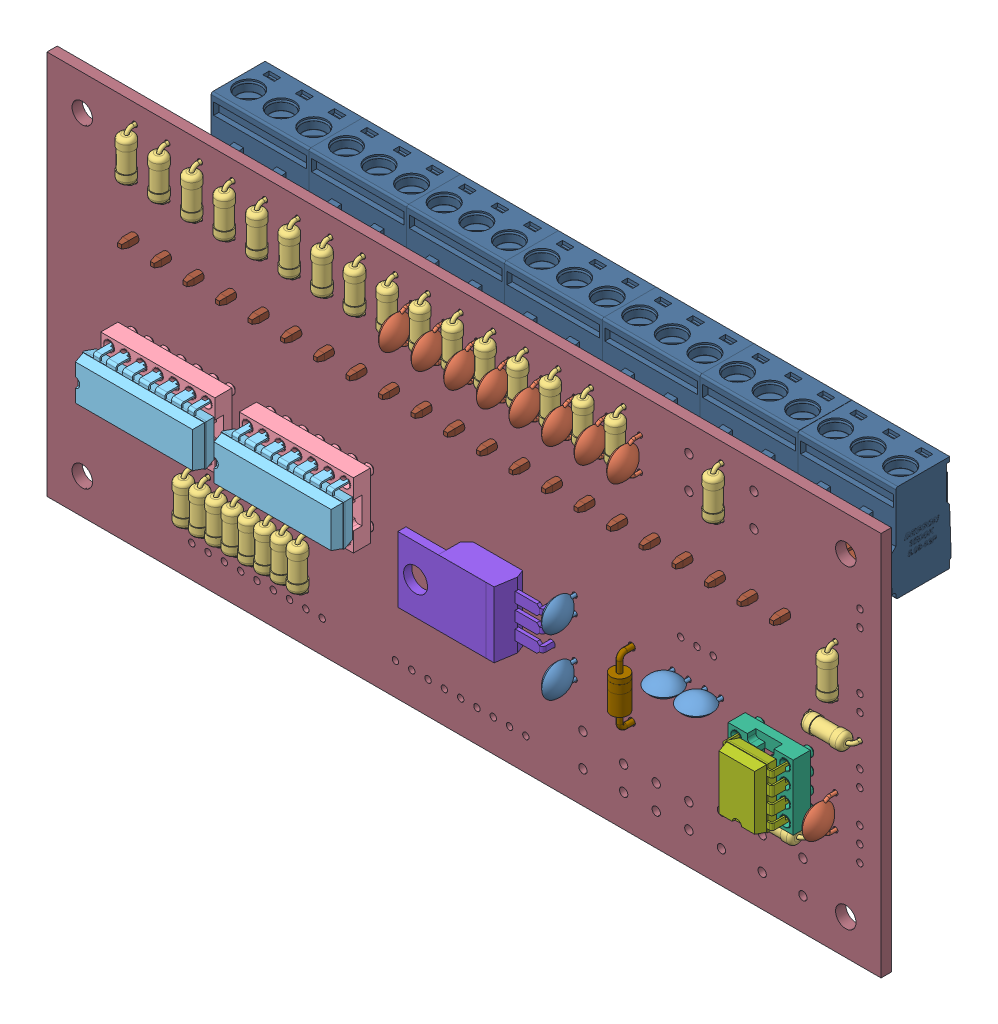
SolidWorks assembly minilab-export, configuration Predeterminado. Lengths in mm.
Overall size (130 60 30.78).
130 component instances, 13 part files, 0 mates.
Components (placement in the parent):
- minilab.step-1: minilab.step [Predeterminado] at (3.7851 -4.1028 7.8934) size (130 60 30.78)
  - C_Disc_D5.0mm_W2.5mm_P2.50mm.step-1: C_Disc_D5.0mm_W2.5mm_P2.50mm.step [Predeterminado] at (175.26 -113.03 1.65) x (0 -1 0) z (0 0 1) size (5 2.5 7.1)
    - SOLID.step-1: SOLID.step [Predeterminado] at origin size (5 2.5 7.1)
  - C_Disc_D5.0mm_W2.5mm_P5.00mm.step-1: C_Disc_D5.0mm_W2.5mm_P5.00mm.step [Predeterminado] at (170.18 -82.55 1.65) x (0 1 0) z (0 0 1) size (5.5 2.5 7.1)
    - SOLID-0.step-1: SOLID-0.step [Predeterminado] at origin size (5.5 2.5 7.1)
  - R_Axial_DIN0207_L6.3mm_D2.5mm_P7.62mm_Horizontal.step-1: R_Axial_DIN0207_L6.3mm_D2.5mm_P7.62mm_Horizontal.step [Predeterminado] at (121.92 -82.55 1.65) x (0 1 0) z (0 0 1) size (8.22 2.5 5.5)
    - SOLID-1.step-1: SOLID-1.step [Predeterminado] at origin size (8.22 2.5 5.5)
  - C_Disc_D5.0mm_W2.5mm_P2.50mm.step_2-1: C_Disc_D5.0mm_W2.5mm_P2.50mm.step_2 [Predeterminado] at (190.52 -106.68 1.65) size (5 2.5 7.1)
    - SOLID.step-1: SOLID.step [Predeterminado] at origin size (5 2.5 7.1)
  - R_Axial_DIN0207_L6.3mm_D2.5mm_P7.62mm_Horizontal.step_2-1: R_Axial_DIN0207_L6.3mm_D2.5mm_P7.62mm_Horizontal.step_2 [Predeterminado] at (182.88 -74.93 1.65) x (0 -1 0) z (0 0 1) size (8.22 2.5 5.5)
    - SOLID-1.step-1: SOLID-1.step [Predeterminado] at origin size (8.22 2.5 5.5)
  - R_Axial_DIN0207_L6.3mm_D2.5mm_P7.62mm_Horizontal.step_3-1: R_Axial_DIN0207_L6.3mm_D2.5mm_P7.62mm_Horizontal.step_3 [Predeterminado] at (198.12 -82.55 1.65) x (0 1 0) z (0 0 1) size (8.22 2.5 5.5)
    - SOLID-1.step-1: SOLID-1.step [Predeterminado] at origin size (8.22 2.5 5.5)
  - C_Disc_D5.0mm_W2.5mm_P5.00mm.step_2-1: C_Disc_D5.0mm_W2.5mm_P5.00mm.step_2 [Predeterminado] at (175.26 -82.51 1.65) x (0 1 0) z (0 0 1) size (5.5 2.5 7.1)
    - SOLID-0.step-1: SOLID-0.step [Predeterminado] at origin size (5.5 2.5 7.1)
  - DIP-14_W7.62mm_Socket.step-1: DIP-14_W7.62mm_Socket.step [Predeterminado] at (106.675 -110.48 1.65) x (0 1 0) z (0 0 1) size (10.16 17.78 7.79)
    - SOLID-2.step-1: SOLID-2.step [Predeterminado] at origin size (10.16 17.78 7.79)
  - DIP-14_W7.62mm.step-1: DIP-14_W7.62mm.step [Predeterminado] at (106.675 -110.48 5.65) x (0 1 0) z (0 0 1) size (7.87 19.05 6.98)
    - SOLID-3.step-1: SOLID-3.step [Predeterminado] at origin size (7.87 19.05 6.98)
  - DIP-8_W7.62mm_Socket.step-1: DIP-8_W7.62mm_Socket.step [Predeterminado] at (212.06 -114.3 1.65) x (-1 0 0) z (0 0 1) size (10.16 10.16 7.79)
    - SOLID-4.step-1: SOLID-4.step [Predeterminado] at origin size (10.16 10.16 7.79)
  - DIP-8_W7.62mm.step-1: DIP-8_W7.62mm.step [Predeterminado] at (212.06 -114.3 5.65) x (-1 0 0) z (0 0 1) size (7.87 9.27 6.98)
    - SOLID-5.step-1: SOLID-5.step [Predeterminado] at origin size (7.87 9.27 6.98)
  - R_Axial_DIN0207_L6.3mm_D2.5mm_P7.62mm_Horizontal.step_4-1: R_Axial_DIN0207_L6.3mm_D2.5mm_P7.62mm_Horizontal.step_4 [Predeterminado] at (127 -82.55 1.65) x (0 1 0) z (0 0 1) size (8.22 2.5 5.5)
    - SOLID-1.step-1: SOLID-1.step [Predeterminado] at origin size (8.22 2.5 5.5)
  - R_Axial_DIN0207_L6.3mm_D2.5mm_P7.62mm_Horizontal.step_5-1: R_Axial_DIN0207_L6.3mm_D2.5mm_P7.62mm_Horizontal.step_5 [Predeterminado] at (125.73 -116.84 1.65) x (0 -1 0) z (0 0 1) size (8.22 2.5 5.5)
    - SOLID-1.step-1: SOLID-1.step [Predeterminado] at origin size (8.22 2.5 5.5)
  - C_Disc_D5.0mm_W2.5mm_P5.00mm.step_3-1: C_Disc_D5.0mm_W2.5mm_P5.00mm.step_3 [Predeterminado] at (149.86 -82.55 1.65) x (0 1 0) z (0 0 1) size (5.5 2.5 7.1)
    - SOLID-0.step-1: SOLID-0.step [Predeterminado] at origin size (5.5 2.5 7.1)
  - TO-220-3_Horizontal_TabUp.step-1: TO-220-3_Horizontal_TabUp.step [Predeterminado] at (171.66 -107.46 1.65) x (0 -1 0) z (0 0 1) size (10.25 19.74 12.58)
    - SOLID-6.step-1: SOLID-6.step [Predeterminado] at origin size (10.25 19.74 12.58)
  - R_Axial_DIN0207_L6.3mm_D2.5mm_P7.62mm_Horizontal.step_6-1: R_Axial_DIN0207_L6.3mm_D2.5mm_P7.62mm_Horizontal.step_6 [Predeterminado] at (133.35 -116.84 1.65) x (0 -1 0) z (0 0 1) size (8.22 2.5 5.5)
    - SOLID-1.step-1: SOLID-1.step [Predeterminado] at origin size (8.22 2.5 5.5)
  - R_Axial_DIN0207_L6.3mm_D2.5mm_P7.62mm_Horizontal.step_7-1: R_Axial_DIN0207_L6.3mm_D2.5mm_P7.62mm_Horizontal.step_7 [Predeterminado] at (120.65 -116.84 1.65) x (0 -1 0) z (0 0 1) size (8.22 2.5 5.5)
    - SOLID-1.step-1: SOLID-1.step [Predeterminado] at origin size (8.22 2.5 5.5)
  - C_Disc_D5.0mm_W2.5mm_P5.00mm.step_4-1: C_Disc_D5.0mm_W2.5mm_P5.00mm.step_4 [Predeterminado] at (180.34 -82.51 1.65) x (0 1 0) z (0 0 1) size (5.5 2.5 7.1)
    - SOLID-0.step-1: SOLID-0.step [Predeterminado] at origin size (5.5 2.5 7.1)
  - R_Axial_DIN0207_L6.3mm_D2.5mm_P7.62mm_Horizontal.step_8-1: R_Axial_DIN0207_L6.3mm_D2.5mm_P7.62mm_Horizontal.step_8 [Predeterminado] at (115.57 -116.84 1.65) x (0 -1 0) z (0 0 1) size (8.22 2.5 5.5)
    - SOLID-1.step-1: SOLID-1.step [Predeterminado] at origin size (8.22 2.5 5.5)
  - R_Axial_DIN0207_L6.3mm_D2.5mm_P7.62mm_Horizontal.step_9-1: R_Axial_DIN0207_L6.3mm_D2.5mm_P7.62mm_Horizontal.step_9 [Predeterminado] at (157.48 -74.93 1.65) x (0 -1 0) z (0 0 1) size (8.22 2.5 5.5)
    - SOLID-1.step-1: SOLID-1.step [Predeterminado] at origin size (8.22 2.5 5.5)
  - R_Axial_DIN0207_L6.3mm_D2.5mm_P7.62mm_Horizontal.step_10-1: R_Axial_DIN0207_L6.3mm_D2.5mm_P7.62mm_Horizontal.step_10 [Predeterminado] at (142.24 -82.55 1.65) x (0 1 0) z (0 0 1) size (8.22 2.5 5.5)
    - SOLID-1.step-1: SOLID-1.step [Predeterminado] at origin size (8.22 2.5 5.5)
  - C_Disc_D5.0mm_W2.5mm_P5.00mm.step_5-1: C_Disc_D5.0mm_W2.5mm_P5.00mm.step_5 [Predeterminado] at (215.88 -110.54 1.65) x (0 -1 0) z (0 0 1) size (5.5 2.5 7.1)
    - SOLID-0.step-1: SOLID-0.step [Predeterminado] at origin size (5.5 2.5 7.1)
  - R_Axial_DIN0207_L6.3mm_D2.5mm_P7.62mm_Horizontal.step_11-1: R_Axial_DIN0207_L6.3mm_D2.5mm_P7.62mm_Horizontal.step_11 [Predeterminado] at (123.19 -116.84 1.65) x (0 -1 0) z (0 0 1) size (8.22 2.5 5.5)
    - SOLID-1.step-1: SOLID-1.step [Predeterminado] at origin size (8.22 2.5 5.5)
  - D_DO-41_SOD81_P10.16mm_Horizontal.step-1: D_DO-41_SOD81_P10.16mm_Horizontal.step [Predeterminado] at (184.15 -106.68 1.65) x (0 -1 0) z (0 0 1) size (10.96 2.72 5.71)
    - SOLID-7.step-1: SOLID-7.step [Predeterminado] at origin size (10.96 2.72 5.71)
  - R_Axial_DIN0207_L6.3mm_D2.5mm_P7.62mm_Horizontal.step_12-1: R_Axial_DIN0207_L6.3mm_D2.5mm_P7.62mm_Horizontal.step_12 [Predeterminado] at (116.84 -82.55 1.65) x (0 1 0) z (0 0 1) size (8.22 2.5 5.5)
    - SOLID-1.step-1: SOLID-1.step [Predeterminado] at origin size (8.22 2.5 5.5)
  - R_Axial_DIN0207_L6.3mm_D2.5mm_P7.62mm_Horizontal.step_13-1: R_Axial_DIN0207_L6.3mm_D2.5mm_P7.62mm_Horizontal.step_13 [Predeterminado] at (132.08 -82.55 1.65) x (0 1 0) z (0 0 1) size (8.22 2.5 5.5)
    - SOLID-1.step-1: SOLID-1.step [Predeterminado] at origin size (8.22 2.5 5.5)
  - R_Axial_DIN0207_L6.3mm_D2.5mm_P7.62mm_Horizontal.step_14-1: R_Axial_DIN0207_L6.3mm_D2.5mm_P7.62mm_Horizontal.step_14 [Predeterminado] at (172.72 -74.93 1.65) x (0 -1 0) z (0 0 1) size (8.22 2.5 5.5)
    - SOLID-1.step-1: SOLID-1.step [Predeterminado] at origin size (8.22 2.5 5.5)
  - R_Axial_DIN0207_L6.3mm_D2.5mm_P7.62mm_Horizontal.step_15-1: R_Axial_DIN0207_L6.3mm_D2.5mm_P7.62mm_Horizontal.step_15 [Predeterminado] at (177.8 -74.93 1.65) x (0 -1 0) z (0 0 1) size (8.22 2.5 5.5)
    - SOLID-1.step-1: SOLID-1.step [Predeterminado] at origin size (8.22 2.5 5.5)
  - R_Axial_DIN0207_L6.3mm_D2.5mm_P7.62mm_Horizontal.step_16-1: R_Axial_DIN0207_L6.3mm_D2.5mm_P7.62mm_Horizontal.step_16 [Predeterminado] at (111.76 -82.55 1.65) x (0 1 0) z (0 0 1) size (8.22 2.5 5.5)
    - SOLID-1.step-1: SOLID-1.step [Predeterminado] at origin size (8.22 2.5 5.5)
  - R_Axial_DIN0207_L6.3mm_D2.5mm_P7.62mm_Horizontal.step_17-1: R_Axial_DIN0207_L6.3mm_D2.5mm_P7.62mm_Horizontal.step_17 [Predeterminado] at (128.27 -116.84 1.65) x (0 -1 0) z (0 0 1) size (8.22 2.5 5.5)
    - SOLID-1.step-1: SOLID-1.step [Predeterminado] at origin size (8.22 2.5 5.5)
  - C_Disc_D5.0mm_W2.5mm_P5.00mm.step_6-1: C_Disc_D5.0mm_W2.5mm_P5.00mm.step_6 [Predeterminado] at (185.42 -82.51 1.65) x (0 1 0) z (0 0 1) size (5.5 2.5 7.1)
    - SOLID-0.step-1: SOLID-0.step [Predeterminado] at origin size (5.5 2.5 7.1)
  - C_Disc_D5.0mm_W2.5mm_P2.50mm.step_3-1: C_Disc_D5.0mm_W2.5mm_P2.50mm.step_3 [Predeterminado] at (175.26 -106.68 1.65) x (0 1 0) z (0 0 1) size (5 2.5 7.1)
    - SOLID.step-1: SOLID.step [Predeterminado] at origin size (5 2.5 7.1)
  - C_Disc_D5.0mm_W2.5mm_P2.50mm.step_4-1: C_Disc_D5.0mm_W2.5mm_P2.50mm.step_4 [Predeterminado] at (198.08 -106.68 1.65) x (-1 0 0) z (0 0 1) size (5 2.5 7.1)
    - SOLID.step-1: SOLID.step [Predeterminado] at origin size (5 2.5 7.1)
  - R_Axial_DIN0207_L6.3mm_D2.5mm_P7.62mm_Horizontal.step_18-1: R_Axial_DIN0207_L6.3mm_D2.5mm_P7.62mm_Horizontal.step_18 [Predeterminado] at (215.9 -90.17 1.65) x (0 -1 0) z (0 0 1) size (8.22 2.5 5.5)
    - SOLID-1.step-1: SOLID-1.step [Predeterminado] at origin size (8.22 2.5 5.5)
  - R_Axial_DIN0207_L6.3mm_D2.5mm_P7.62mm_Horizontal.step_19-1: R_Axial_DIN0207_L6.3mm_D2.5mm_P7.62mm_Horizontal.step_19 [Predeterminado] at (219.69 -101.61 1.65) x (-1 0 0) z (0 0 1) size (8.22 2.5 5.5)
    - SOLID-1.step-1: SOLID-1.step [Predeterminado] at origin size (8.22 2.5 5.5)
  - C_Disc_D5.0mm_W2.5mm_P5.00mm.step_7-1: C_Disc_D5.0mm_W2.5mm_P5.00mm.step_7 [Predeterminado] at (160.02 -82.55 1.65) x (0 1 0) z (0 0 1) size (5.5 2.5 7.1)
    - SOLID-0.step-1: SOLID-0.step [Predeterminado] at origin size (5.5 2.5 7.1)
  - C_Disc_D5.0mm_W2.5mm_P5.00mm.step_8-1: C_Disc_D5.0mm_W2.5mm_P5.00mm.step_8 [Predeterminado] at (165.1 -82.55 1.65) x (0 1 0) z (0 0 1) size (5.5 2.5 7.1)
    - SOLID-0.step-1: SOLID-0.step [Predeterminado] at origin size (5.5 2.5 7.1)
  - R_Axial_DIN0207_L6.3mm_D2.5mm_P7.62mm_Horizontal.step_20-1: R_Axial_DIN0207_L6.3mm_D2.5mm_P7.62mm_Horizontal.step_20 [Predeterminado] at (137.16 -82.55 1.65) x (0 1 0) z (0 0 1) size (8.22 2.5 5.5)
    - SOLID-1.step-1: SOLID-1.step [Predeterminado] at origin size (8.22 2.5 5.5)
  - R_Axial_DIN0207_L6.3mm_D2.5mm_P7.62mm_Horizontal.step_21-1: R_Axial_DIN0207_L6.3mm_D2.5mm_P7.62mm_Horizontal.step_21 [Predeterminado] at (130.81 -116.84 1.65) x (0 -1 0) z (0 0 1) size (8.22 2.5 5.5)
    - SOLID-1.step-1: SOLID-1.step [Predeterminado] at origin size (8.22 2.5 5.5)
  - R_Axial_DIN0207_L6.3mm_D2.5mm_P7.62mm_Horizontal.step_22-1: R_Axial_DIN0207_L6.3mm_D2.5mm_P7.62mm_Horizontal.step_22 [Predeterminado] at (204.45 -118.12 1.65) size (8.22 2.5 5.5)
    - SOLID-1.step-1: SOLID-1.step [Predeterminado] at origin size (8.22 2.5 5.5)
  - R_Axial_DIN0207_L6.3mm_D2.5mm_P7.62mm_Horizontal.step_23-1: R_Axial_DIN0207_L6.3mm_D2.5mm_P7.62mm_Horizontal.step_23 [Predeterminado] at (118.11 -116.84 1.65) x (0 -1 0) z (0 0 1) size (8.22 2.5 5.5)
    - SOLID-1.step-1: SOLID-1.step [Predeterminado] at origin size (8.22 2.5 5.5)
  - R_Axial_DIN0207_L6.3mm_D2.5mm_P7.62mm_Horizontal.step_24-1: R_Axial_DIN0207_L6.3mm_D2.5mm_P7.62mm_Horizontal.step_24 [Predeterminado] at (106.68 -82.55 1.65) x (0 1 0) z (0 0 1) size (8.22 2.5 5.5)
    - SOLID-1.step-1: SOLID-1.step [Predeterminado] at origin size (8.22 2.5 5.5)
  - R_Axial_DIN0207_L6.3mm_D2.5mm_P7.62mm_Horizontal.step_25-1: R_Axial_DIN0207_L6.3mm_D2.5mm_P7.62mm_Horizontal.step_25 [Predeterminado] at (167.64 -74.93 1.65) x (0 -1 0) z (0 0 1) size (8.22 2.5 5.5)
    - SOLID-1.step-1: SOLID-1.step [Predeterminado] at origin size (8.22 2.5 5.5)
  - R_Axial_DIN0207_L6.3mm_D2.5mm_P7.62mm_Horizontal.step_26-1: R_Axial_DIN0207_L6.3mm_D2.5mm_P7.62mm_Horizontal.step_26 [Predeterminado] at (162.56 -74.93 1.65) x (0 -1 0) z (0 0 1) size (8.22 2.5 5.5)
    - SOLID-1.step-1: SOLID-1.step [Predeterminado] at origin size (8.22 2.5 5.5)
  - R_Axial_DIN0207_L6.3mm_D2.5mm_P7.62mm_Horizontal.step_27-1: R_Axial_DIN0207_L6.3mm_D2.5mm_P7.62mm_Horizontal.step_27 [Predeterminado] at (147.32 -74.93 1.65) x (0 -1 0) z (0 0 1) size (8.22 2.5 5.5)
    - SOLID-1.step-1: SOLID-1.step [Predeterminado] at origin size (8.22 2.5 5.5)
  - DIP-14_W7.62mm_Socket.step_2-1: DIP-14_W7.62mm_Socket.step_2 [Predeterminado] at (128.265 -110.48 1.65) x (0 1 0) z (0 0 1) size (10.16 17.78 7.79)
    - SOLID-2.step-1: SOLID-2.step [Predeterminado] at origin size (10.16 17.78 7.79)
  - DIP-14_W7.62mm.step_2-1: DIP-14_W7.62mm.step_2 [Predeterminado] at (128.265 -110.48 5.65) x (0 1 0) z (0 0 1) size (7.87 19.05 6.98)
    - SOLID-3.step-1: SOLID-3.step [Predeterminado] at origin size (7.87 19.05 6.98)
  - R_Axial_DIN0207_L6.3mm_D2.5mm_P7.62mm_Horizontal.step_28-1: R_Axial_DIN0207_L6.3mm_D2.5mm_P7.62mm_Horizontal.step_28 [Predeterminado] at (152.4 -74.93 1.65) x (0 -1 0) z (0 0 1) size (8.22 2.5 5.5)
    - SOLID-1.step-1: SOLID-1.step [Predeterminado] at origin size (8.22 2.5 5.5)
  - C_Disc_D5.0mm_W2.5mm_P5.00mm.step_9-1: C_Disc_D5.0mm_W2.5mm_P5.00mm.step_9 [Predeterminado] at (154.94 -82.55 1.65) x (0 1 0) z (0 0 1) size (5.5 2.5 7.1)
    - SOLID-0.step-1: SOLID-0.step [Predeterminado] at origin size (5.5 2.5 7.1)
  - 2EDGK-5.08-03P-14-00AH.step-1: 2EDGK-5.08-03P-14-00AH.step [Predeterminado] at (104.14 -94.21 -4.05) x (1 0 0) z (0 1 0) size (15.24 17.4 15.1)
    - SOLID-8.step-1: SOLID-8.step [Predeterminado] at origin size (15.24 17.4 15.1)
  - 2EDGV-5.08-03P-14-00AH.step-1: 2EDGV-5.08-03P-14-00AH.step [Predeterminado] at (104.14 -93.91 -0.05) x (1 0 0) z (0 1 0) size (15.24 16.1 8.2)
    - SOLID-9.step-1: SOLID-9.step [Predeterminado] at origin size (15.24 16.1 8.2)
  - 2EDGK-5.08-03P-14-00AH.step_2-1: 2EDGK-5.08-03P-14-00AH.step_2 [Predeterminado] at (134.62 -94.21 -4.05) x (1 0 0) z (0 1 0) size (15.24 17.4 15.1)
    - SOLID-8.step-1: SOLID-8.step [Predeterminado] at origin size (15.24 17.4 15.1)
  - 2EDGV-5.08-03P-14-00AH.step_2-1: 2EDGV-5.08-03P-14-00AH.step_2 [Predeterminado] at (134.62 -93.91 -0.05) x (1 0 0) z (0 1 0) size (15.24 16.1 8.2)
    - SOLID-9.step-1: SOLID-9.step [Predeterminado] at origin size (15.24 16.1 8.2)
  - 2EDGK-5.08-03P-14-00AH.step_3-1: 2EDGK-5.08-03P-14-00AH.step_3 [Predeterminado] at (149.86 -94.21 -4.05) x (1 0 0) z (0 1 0) size (15.24 17.4 15.1)
    - SOLID-8.step-1: SOLID-8.step [Predeterminado] at origin size (15.24 17.4 15.1)
  - 2EDGV-5.08-03P-14-00AH.step_3-1: 2EDGV-5.08-03P-14-00AH.step_3 [Predeterminado] at (149.86 -93.91 -0.05) x (1 0 0) z (0 1 0) size (15.24 16.1 8.2)
    - SOLID-9.step-1: SOLID-9.step [Predeterminado] at origin size (15.24 16.1 8.2)
  - SOIC-8-1EP_3.9x4.9mm_P1.27mm_EP2.35x2.35mm.step-1: SOIC-8-1EP_3.9x4.9mm_P1.27mm_EP2.35x2.35mm.step [Predeterminado] at (194.31 -114.3 -0.05) x (-1 0 0) z (0 0 -1) size (6 4.9 1.75)
    - SOLID-10.step-1: SOLID-10.step [Predeterminado] at origin size (6 4.9 1.75)
  - 2EDGK-5.08-03P-14-00AH.step_4-1: 2EDGK-5.08-03P-14-00AH.step_4 [Predeterminado] at (165.1 -94.21 -4.05) x (1 0 0) z (0 1 0) size (15.24 17.4 15.1)
    - SOLID-8.step-1: SOLID-8.step [Predeterminado] at origin size (15.24 17.4 15.1)
  - 2EDGV-5.08-03P-14-00AH.step_4-1: 2EDGV-5.08-03P-14-00AH.step_4 [Predeterminado] at (165.1 -93.91 -0.05) x (1 0 0) z (0 1 0) size (15.24 16.1 8.2)
    - SOLID-9.step-1: SOLID-9.step [Predeterminado] at origin size (15.24 16.1 8.2)
  - 2EDGK-5.08-03P-14-00AH.step_5-1: 2EDGK-5.08-03P-14-00AH.step_5 [Predeterminado] at (180.34 -94.21 -4.05) x (1 0 0) z (0 1 0) size (15.24 17.4 15.1)
    - SOLID-8.step-1: SOLID-8.step [Predeterminado] at origin size (15.24 17.4 15.1)
  - 2EDGV-5.08-03P-14-00AH.step_5-1: 2EDGV-5.08-03P-14-00AH.step_5 [Predeterminado] at (180.34 -93.91 -0.05) x (1 0 0) z (0 1 0) size (15.24 16.1 8.2)
    - SOLID-9.step-1: SOLID-9.step [Predeterminado] at origin size (15.24 16.1 8.2)
  - 2EDGK-5.08-03P-14-00AH.step_6-1: 2EDGK-5.08-03P-14-00AH.step_6 [Predeterminado] at (119.38 -94.21 -4.05) x (1 0 0) z (0 1 0) size (15.24 17.4 15.1)
    - SOLID-8.step-1: SOLID-8.step [Predeterminado] at origin size (15.24 17.4 15.1)
  - 2EDGV-5.08-03P-14-00AH.step_6-1: 2EDGV-5.08-03P-14-00AH.step_6 [Predeterminado] at (119.38 -93.91 -0.05) x (1 0 0) z (0 1 0) size (15.24 16.1 8.2)
    - SOLID-9.step-1: SOLID-9.step [Predeterminado] at origin size (15.24 16.1 8.2)
  - 2EDGK-5.08-03P-14-00AH.step_7-1: 2EDGK-5.08-03P-14-00AH.step_7 [Predeterminado] at (195.615 -94.21 -4.05) x (1 0 0) z (0 1 0) size (15.24 17.4 15.1)
    - SOLID-8.step-1: SOLID-8.step [Predeterminado] at origin size (15.24 17.4 15.1)
  - 2EDGV-5.08-03P-14-00AH.step_7-1: 2EDGV-5.08-03P-14-00AH.step_7 [Predeterminado] at (195.575 -93.91 -0.05) x (1 0 0) z (0 1 0) size (15.24 16.1 8.2)
    - SOLID-9.step-1: SOLID-9.step [Predeterminado] at origin size (15.24 16.1 8.2)
  - minilab PCB.step-1: minilab PCB.step [Predeterminado] at origin size (130 60 1.6)
